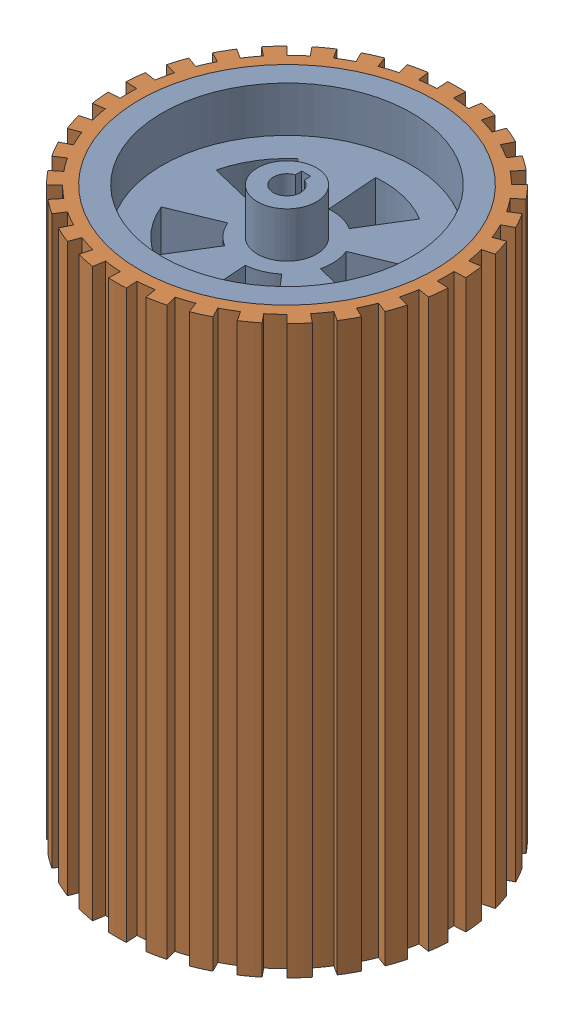
SolidWorks assembly wheel assembly 250mm, configuration Default. Lengths in mm.
Overall size (149.8 250 150).
2 component instances, 2 part files, 3 mates.
Components (placement in the parent):
- wheel rim-1: wheel rim [Default] at (66.9065 32.6377 272.2951) size (130 250 130)
- wheel rubber-1: wheel rubber [Default] at (66.9065 32.6377 272.2951) size (149.8 250 150)
Mates (geometry in assembly coordinates):
- Concentric1: concentric aligned: circle of wheel rim-1; circle of wheel rubber-1
- Coincident2: coincident aligned: circle of wheel rim-1; circle of wheel rubber-1
- Lock1: lock: unknown of wheel rim-1; unknown of wheel rubber-1
